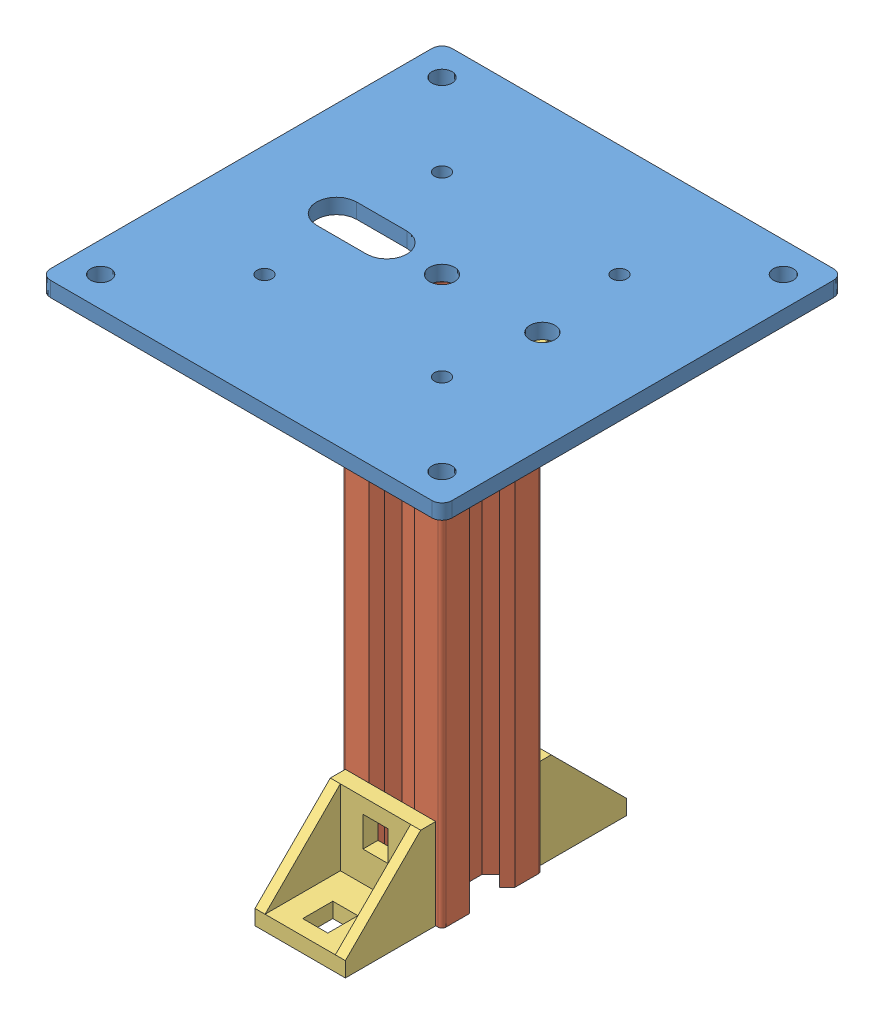
SolidWorks assembly mat_balise nu, configuration Default. Lengths in mm.
Overall size (80 103 80).
5 component instances, 3 part files, 12 mates.
Components (placement in the parent):
- plaque_support_80x80-3: plaque_support_80x80 [Default] at (-30.8591 -54.0529 28.0788) size (80 3 80)
- Profilé Aluminium Rexroth 20x20 L100-1: Profilé Aluminium Rexroth 20x20 L100 [Default] at (9.1409 -154.0529 -11.9212) size (20 100 20)
- CornerXD_Rexroth_18x18-1: CornerXD_Rexroth_18x18 [Default] at (19.1409 -54.0529 -2.6712) x (0 0 -1) z (0 -1 0) size (18 18 18)
- CornerXD_Rexroth_18x18-2: CornerXD_Rexroth_18x18 [Default] at (17.8909 -154.0529 -1.9212) x (-1 0 0) z (0 1 0) size (18 18 18)
- CornerXD_Rexroth_18x18-3: CornerXD_Rexroth_18x18 [Default] at (-0.1091 -154.0529 -21.9212) x (1 0 0) z (0 1 0) size (18 18 18)
Mates (geometry in assembly coordinates):
- Coaxiale19: concentric aligned: cylinder of plaque_support_80x80-3 through (9.1409 -51.0529 -11.9212) axis (0 -1 0) radius 2.5; cylinder of Profilé Aluminium Rexroth 20x20 L100-1 through (9.1409 -54.0529 -11.9212) axis (0 -1 0) radius 2.5
- Coïncidente30: coincident anti-aligned: plane of plaque_support_80x80-3; plane of Profilé Aluminium Rexroth 20x20 L100-1
- Parallèle1: parallel aligned: plane of plaque_support_80x80-3; plane of Profilé Aluminium Rexroth 20x20 L100-1
- Coïncidente32: coincident anti-aligned: plane of Profilé Aluminium Rexroth 20x20 L100-1; plane of CornerXD_Rexroth_18x18-1
- Coïncidente33: coincident anti-aligned: plane of plaque_support_80x80-3; plane of CornerXD_Rexroth_18x18-1
- Coïncidente35: coincident: line of Profilé Aluminium Rexroth 20x20 L100-1 through (19.1409 -54.0529 -2.6712) axis (0 -1 0); plane of CornerXD_Rexroth_18x18-1
- Coïncidente36: coincident aligned: plane of CornerXD_Rexroth_18x18-2; plane of Profilé Aluminium Rexroth 20x20 L100-1
- Coïncidente37: coincident anti-aligned: plane of CornerXD_Rexroth_18x18-2; plane of Profilé Aluminium Rexroth 20x20 L100-1
- Coïncidente38: coincident aligned: plane of CornerXD_Rexroth_18x18-3; plane of Profilé Aluminium Rexroth 20x20 L100-1
- Coïncidente39: coincident anti-aligned: plane of Profilé Aluminium Rexroth 20x20 L100-1; plane of CornerXD_Rexroth_18x18-3
- Coïncidente40: coincident aligned: plane of CornerXD_Rexroth_18x18-2; plane of CornerXD_Rexroth_18x18-3
- Coïncidente41: coincident aligned: line of Profilé Aluminium Rexroth 20x20 L100-1 through (-0.1091 -54.0529 -1.9212) axis (0 -1 0); line of CornerXD_Rexroth_18x18-2 through (-0.1091 -136.0529 -1.9212) axis (0 -1 0)
